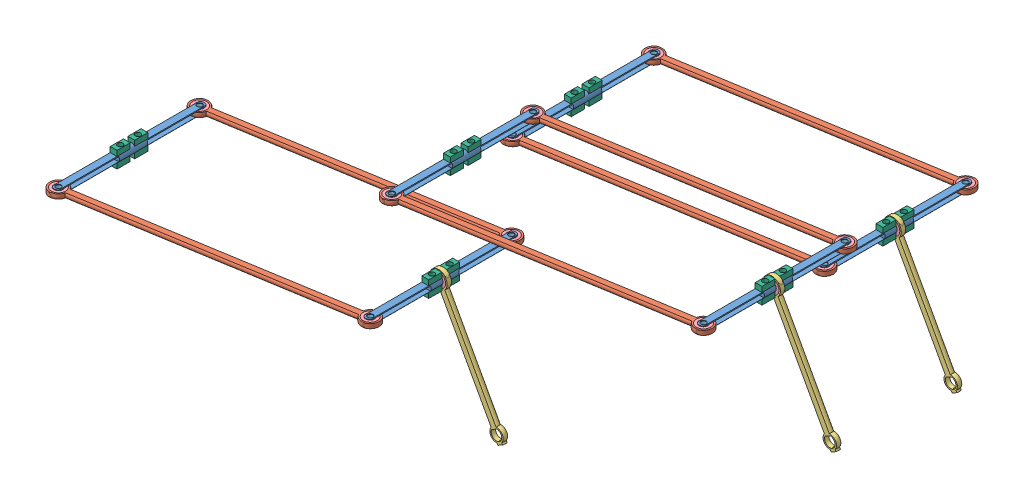
SolidWorks assembly Delta臂, configuration 默认. Lengths in mm.
Overall size (308.28 87.18 271.4).
69 component instances, 6 part files, 0 mates.
Components (placement in the parent):
- 单臂-1: 单臂 [默认] at origin size (196.95 72.97 116.28)
  - 关节-1: 关节 [默认] at (38.3387 -1.1505 -161.6361) size (5 5 85)
  - 关节-2: 关节 [默认] at (-113.5016 -1.1505 -136.8395) size (5 5 85)
  - 长臂-1: 长臂 [默认] at (-126.4048 -1.1505 -124.7323) x (0.986926 0 -0.161172) z (0.161172 0 0.986926) size (163.85 2.5 10)
  - 长臂-2: 长臂 [默认] at (-126.4048 -1.1505 -44.7323) x (0.986926 0 -0.161172) z (0.161172 0 0.986926) size (163.85 2.5 10)
  - 短臂-1: 短臂 [默认] at (78.8008 -74.9015 -111.6361) x (-0.480997 0.876722 0) z (0.876722 0.480997 0) size (77.74 2.5 10)
  - 轴承_MR85ZZ-1: 轴承_MR85ZZ [默认] at (38.3387 -1.1505 -112.8861) size (8 8 2.5)
  - 轴承_MR85ZZ-2: 轴承_MR85ZZ [默认] at (38.3387 0.0995 -71.6361) x (1 0 0) z (0 -1 0) size (8 8 2.5)
  - 轴承_MR85ZZ-3: 轴承_MR85ZZ [默认] at (-113.5016 0.0995 -46.8395) x (1 0 0) z (0 -1 0) size (8 8 2.5)
  - 轴承_MR85ZZ-4: 轴承_MR85ZZ [默认] at (-113.5016 0.0995 -126.8395) x (1 0 0) z (0 -1 0) size (8 8 2.5)
  - 轴承_MR85ZZ-5: 轴承_MR85ZZ [默认] at (38.3387 0.0995 -151.6361) x (1 0 0) z (0 -1 0) size (8 8 2.5)
  - 长臂_关节连接件-1: 长臂_关节连接件 [默认] at (-113.5016 -2.4005 -126.8395) x (1 0 0) z (0 1 0) size (5 5 2.5)
  - 长臂_关节连接件-2: 长臂_关节连接件 [默认] at (38.3387 0.0995 -151.6361) x (1 0 0) z (0 -1 0) size (5 5 2.5)
  - 长臂_关节连接件-3: 长臂_关节连接件 [默认] at (38.3387 0.0995 -71.6361) x (1 0 0) z (0 -1 0) size (5 5 2.5)
  - 长臂_关节连接件-4: 长臂_关节连接件 [默认] at (-113.5016 0.0995 -46.8395) x (1 0 0) z (0 -1 0) size (5 5 2.5)
  - 短臂-关节轴承限位件-1: 短臂-关节轴承限位件 [默认] at (-115.3656 3.4495 -82.9304) x (0 0 1) z (0 -1 0) size (7.5 3.84 3)
  - 短臂-关节轴承限位件-2: 短臂-关节轴承限位件 [默认] at (-115.3656 -2.7505 -92.9304) x (0 0 1) z (0 -1 0) size (7.5 3.84 3)
  - 短臂-关节轴承限位件-3: 短臂-关节轴承限位件 [默认] at (-115.3656 3.4495 -92.9304) x (0 0 1) z (0 -1 0) size (7.5 3.84 3)
  - 短臂-关节轴承限位件-4: 短臂-关节轴承限位件 [默认] at (-115.3656 -2.7505 -82.9304) x (0 0 1) z (0 -1 0) size (7.5 3.84 3)
  - 短臂-关节轴承限位件-5: 短臂-关节轴承限位件 [默认] at (36.4746 -2.7505 -117.727) x (0 0 1) z (0 -1 0) size (7.5 3.84 3)
  - 短臂-关节轴承限位件-6: 短臂-关节轴承限位件 [默认] at (36.4746 3.4495 -107.727) x (0 0 1) z (0 -1 0) size (7.5 3.84 3)
  - 短臂-关节轴承限位件-7: 短臂-关节轴承限位件 [默认] at (36.4746 3.4495 -117.727) x (0 0 1) z (0 -1 0) size (7.5 3.84 3)
  - 短臂-关节轴承限位件-8: 短臂-关节轴承限位件 [默认] at (36.4746 -2.7505 -107.727) x (0 0 1) z (0 -1 0) size (7.5 3.84 3)
- 单臂-2: 单臂 [默认] at (5.4826 10.7791 73.9916) size (196.95 72.97 116.28)
  - 关节-1: 关节 [默认] at (38.3387 -1.1505 -161.6361) size (5 5 85)
  - 关节-2: 关节 [默认] at (-113.5016 -1.1505 -136.8395) size (5 5 85)
  - 长臂-1: 长臂 [默认] at (-126.4048 -1.1505 -124.7323) x (0.986926 0 -0.161172) z (0.161172 0 0.986926) size (163.85 2.5 10)
  - 长臂-2: 长臂 [默认] at (-126.4048 -1.1505 -44.7323) x (0.986926 0 -0.161172) z (0.161172 0 0.986926) size (163.85 2.5 10)
  - 短臂-1: 短臂 [默认] at (78.8008 -74.9015 -111.6361) x (-0.480997 0.876722 0) z (0.876722 0.480997 0) size (77.74 2.5 10)
  - 轴承_MR85ZZ-1: 轴承_MR85ZZ [默认] at (38.3387 -1.1505 -112.8861) size (8 8 2.5)
  - 轴承_MR85ZZ-2: 轴承_MR85ZZ [默认] at (38.3387 0.0995 -71.6361) x (1 0 0) z (0 -1 0) size (8 8 2.5)
  - 轴承_MR85ZZ-3: 轴承_MR85ZZ [默认] at (-113.5016 0.0995 -46.8395) x (1 0 0) z (0 -1 0) size (8 8 2.5)
  - 轴承_MR85ZZ-4: 轴承_MR85ZZ [默认] at (-113.5016 0.0995 -126.8395) x (1 0 0) z (0 -1 0) size (8 8 2.5)
  - 轴承_MR85ZZ-5: 轴承_MR85ZZ [默认] at (38.3387 0.0995 -151.6361) x (1 0 0) z (0 -1 0) size (8 8 2.5)
  - 长臂_关节连接件-1: 长臂_关节连接件 [默认] at (-113.5016 -2.4005 -126.8395) x (1 0 0) z (0 1 0) size (5 5 2.5)
  - 长臂_关节连接件-2: 长臂_关节连接件 [默认] at (38.3387 0.0995 -151.6361) x (1 0 0) z (0 -1 0) size (5 5 2.5)
  - 长臂_关节连接件-3: 长臂_关节连接件 [默认] at (38.3387 0.0995 -71.6361) x (1 0 0) z (0 -1 0) size (5 5 2.5)
  - 长臂_关节连接件-4: 长臂_关节连接件 [默认] at (-113.5016 0.0995 -46.8395) x (1 0 0) z (0 -1 0) size (5 5 2.5)
  - 短臂-关节轴承限位件-1: 短臂-关节轴承限位件 [默认] at (-115.3656 3.4495 -82.9304) x (0 0 1) z (0 -1 0) size (7.5 3.84 3)
  - 短臂-关节轴承限位件-2: 短臂-关节轴承限位件 [默认] at (-115.3656 -2.7505 -92.9304) x (0 0 1) z (0 -1 0) size (7.5 3.84 3)
  - 短臂-关节轴承限位件-3: 短臂-关节轴承限位件 [默认] at (-115.3656 3.4495 -92.9304) x (0 0 1) z (0 -1 0) size (7.5 3.84 3)
  - 短臂-关节轴承限位件-4: 短臂-关节轴承限位件 [默认] at (-115.3656 -2.7505 -82.9304) x (0 0 1) z (0 -1 0) size (7.5 3.84 3)
  - 短臂-关节轴承限位件-5: 短臂-关节轴承限位件 [默认] at (36.4746 -2.7505 -117.727) x (0 0 1) z (0 -1 0) size (7.5 3.84 3)
  - 短臂-关节轴承限位件-6: 短臂-关节轴承限位件 [默认] at (36.4746 3.4495 -107.727) x (0 0 1) z (0 -1 0) size (7.5 3.84 3)
  - 短臂-关节轴承限位件-7: 短臂-关节轴承限位件 [默认] at (36.4746 3.4495 -117.727) x (0 0 1) z (0 -1 0) size (7.5 3.84 3)
  - 短臂-关节轴承限位件-8: 短臂-关节轴承限位件 [默认] at (36.4746 -2.7505 -107.727) x (0 0 1) z (0 -1 0) size (7.5 3.84 3)
- 单臂-3: 单臂 [默认] at (-106.4393 -3.4328 150.9692) size (196.95 72.97 116.28)
  - 关节-1: 关节 [默认] at (38.3387 -1.1505 -161.6361) size (5 5 85)
  - 关节-2: 关节 [默认] at (-113.5016 -1.1505 -136.8395) size (5 5 85)
  - 长臂-1: 长臂 [默认] at (-126.4048 -1.1505 -124.7323) x (0.986926 0 -0.161172) z (0.161172 0 0.986926) size (163.85 2.5 10)
  - 长臂-2: 长臂 [默认] at (-126.4048 -1.1505 -44.7323) x (0.986926 0 -0.161172) z (0.161172 0 0.986926) size (163.85 2.5 10)
  - 短臂-1: 短臂 [默认] at (78.8008 -74.9015 -111.6361) x (-0.480997 0.876722 0) z (0.876722 0.480997 0) size (77.74 2.5 10)
  - 轴承_MR85ZZ-1: 轴承_MR85ZZ [默认] at (38.3387 -1.1505 -112.8861) size (8 8 2.5)
  - 轴承_MR85ZZ-2: 轴承_MR85ZZ [默认] at (38.3387 0.0995 -71.6361) x (1 0 0) z (0 -1 0) size (8 8 2.5)
  - 轴承_MR85ZZ-3: 轴承_MR85ZZ [默认] at (-113.5016 0.0995 -46.8395) x (1 0 0) z (0 -1 0) size (8 8 2.5)
  - 轴承_MR85ZZ-4: 轴承_MR85ZZ [默认] at (-113.5016 0.0995 -126.8395) x (1 0 0) z (0 -1 0) size (8 8 2.5)
  - 轴承_MR85ZZ-5: 轴承_MR85ZZ [默认] at (38.3387 0.0995 -151.6361) x (1 0 0) z (0 -1 0) size (8 8 2.5)
  - 长臂_关节连接件-1: 长臂_关节连接件 [默认] at (-113.5016 -2.4005 -126.8395) x (1 0 0) z (0 1 0) size (5 5 2.5)
  - 长臂_关节连接件-2: 长臂_关节连接件 [默认] at (38.3387 0.0995 -151.6361) x (1 0 0) z (0 -1 0) size (5 5 2.5)
  - 长臂_关节连接件-3: 长臂_关节连接件 [默认] at (38.3387 0.0995 -71.6361) x (1 0 0) z (0 -1 0) size (5 5 2.5)
  - 长臂_关节连接件-4: 长臂_关节连接件 [默认] at (-113.5016 0.0995 -46.8395) x (1 0 0) z (0 -1 0) size (5 5 2.5)
  - 短臂-关节轴承限位件-1: 短臂-关节轴承限位件 [默认] at (-115.3656 3.4495 -82.9304) x (0 0 1) z (0 -1 0) size (7.5 3.84 3)
  - 短臂-关节轴承限位件-2: 短臂-关节轴承限位件 [默认] at (-115.3656 -2.7505 -92.9304) x (0 0 1) z (0 -1 0) size (7.5 3.84 3)
  - 短臂-关节轴承限位件-3: 短臂-关节轴承限位件 [默认] at (-115.3656 3.4495 -92.9304) x (0 0 1) z (0 -1 0) size (7.5 3.84 3)
  - 短臂-关节轴承限位件-4: 短臂-关节轴承限位件 [默认] at (-115.3656 -2.7505 -82.9304) x (0 0 1) z (0 -1 0) size (7.5 3.84 3)
  - 短臂-关节轴承限位件-5: 短臂-关节轴承限位件 [默认] at (36.4746 -2.7505 -117.727) x (0 0 1) z (0 -1 0) size (7.5 3.84 3)
  - 短臂-关节轴承限位件-6: 短臂-关节轴承限位件 [默认] at (36.4746 3.4495 -107.727) x (0 0 1) z (0 -1 0) size (7.5 3.84 3)
  - 短臂-关节轴承限位件-7: 短臂-关节轴承限位件 [默认] at (36.4746 3.4495 -117.727) x (0 0 1) z (0 -1 0) size (7.5 3.84 3)
  - 短臂-关节轴承限位件-8: 短臂-关节轴承限位件 [默认] at (36.4746 -2.7505 -107.727) x (0 0 1) z (0 -1 0) size (7.5 3.84 3)
